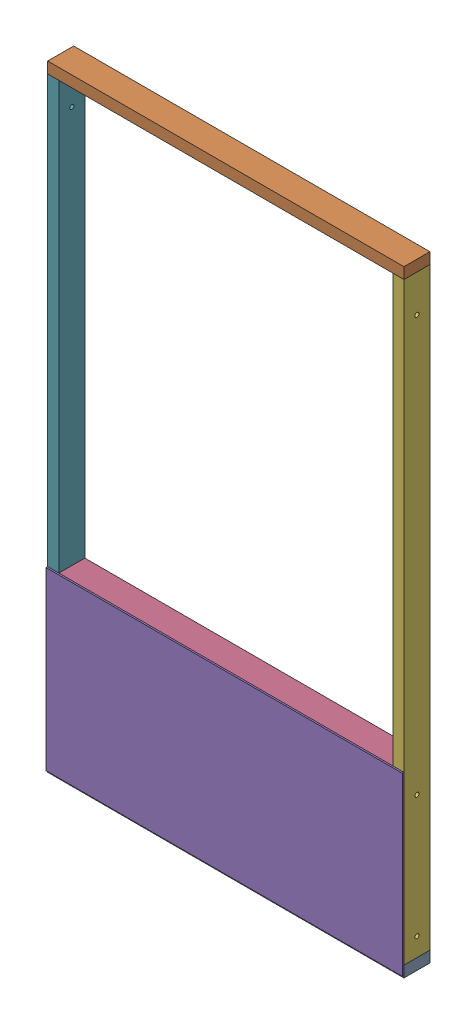
SolidWorks assembly basic panelC, configuration Default. Lengths in mm.
Overall size (1219.2 2108.2 94.46).
7 component instances, 6 part files, 34 mates.
Components (placement in the parent):
- 2x4x48-1: 2x4x48 [Default] x (0 0 -1) z (0 1 0) size (88.9 1219.2 38.1)
- 2x4x48-2: 2x4x48 [Default] at (0 2070.1 0) x (0 0 1) z (0 -1 0) size (88.9 1219.2 38.1)
- 2x4x21-1: 2x4x21 [Default] at (-609.6 552.45 0) x (0 0 -1) z (-1 0 0) size (88.9 533.4 38.1)
- 2x4x45-1: 2x4x45 [Default] at (-38.1 571.5 0) x (0 0 1) z (0 -1 0) size (88.9 1143 38.1)
- plywoodx48x23.7 plywood-1: plywoodx48x23.7 plywood [Default] at (-609.6 289.56 44.45) x (1 0 0) z (0 -1 0) size (1219.2 5.56 601.98)
- 2x4x80-HoleB-2: 2x4x80-HoleB [Default] at (-19.05 19.05 0) x (0 0 1) z (-1 0 0) size (88.9 2032 38.1)
- 2x4x80-Hole-2: 2x4x80-Hole [Default] at (-1200.15 19.05 0) x (0 0 -1) z (1 0 0) size (88.9 2032 38.1)
Mates (geometry in assembly coordinates):
- Coincident10: coincident anti-aligned: plane of 2x4x48-1 through (-1219.2 19.05 44.45) normal (0 1 0); plane of 2x4x21-1 through (-609.6 19.05 0) normal (0 -1 0)
- Coincident11: coincident aligned: plane of 2x4x48-1 through (-1219.2 19.05 44.45) normal (0 0 1); plane of 2x4x21-1 through (-628.65 19.05 44.45) normal (0 0 1)
- Coincident12: coincident anti-aligned: plane of 2x4x21-1 through (-609.6 552.45 0) normal (0 1 0); plane of 2x4x45-1 through (-1181.1 552.45 -44.45) normal (0 -1 0)
- Coincident13: coincident aligned: plane of 2x4x21-1 through (-628.65 19.05 44.45) normal (0 0 1); plane of 2x4x45-1 through (-1181.1 552.45 44.45) normal (0 0 1)
- Coincident18: coincident anti-aligned: plane of 2x4x48-1 through (-1219.2 19.05 44.45) normal (0 1 0); plane of 2x4x80-Hole-2 through (-1200.15 19.05 0) normal (0 -1 0)
- Coincident19: coincident aligned: plane of 2x4x48-1 through (-1219.2 0 0) normal (-1 0 0); plane of 2x4x80-Hole-2 through (-1219.2 2051.05 -44.45) normal (-1 0 0)
- Coincident20: coincident aligned: plane of 2x4x48-1 through (-1219.2 19.05 -44.45) normal (0 0 -1); plane of 2x4x80-Hole-2 through (-1219.2 2051.05 -44.45) normal (0 0 -1)
- Coincident21: coincident anti-aligned: plane of 2x4x48-1 through (-1219.2 19.05 44.45) normal (0 1 0); plane of 2x4x80-Hole-1 through (-19.05 19.05 0) normal (0 -1 0)
- Coincident22: coincident aligned: plane of 2x4x48-1 through (0 0 0) normal (1 0 0); plane of 2x4x80-Hole-1 through (0 2051.05 44.45) normal (1 0 0)
- Coincident24: coincident aligned: plane of 2x4x48-1 through (-1219.2 19.05 -44.45) normal (0 0 -1); plane of 2x4x80-Hole-1 through (0 2051.05 -44.45) normal (0 0 -1)
- Coincident26: coincident anti-aligned: plane of 2x4x45-1 through (-38.1 571.5 0) normal (1 0 0); plane of 2x4x80-Hole-1 through (-38.1 2051.05 44.45) normal (-1 0 0)
- Symmetric1: symmetric aligned: plane of 2x4x48-1 through (0 0 0) normal (1 0 0); plane of 2x4x21-1 through (-1219.2 0 0) normal (-1 0 0); plane of 2x4x48-1 through (-609.6 552.45 0) normal (-1 0 0)
- Coincident27: coincident anti-aligned: plane of 2x4x48-2 through (-1219.2 2051.05 -44.45) normal (0 -1 0); plane of 2x4x80-Hole-2 through (-1200.15 2051.05 0) normal (0 1 0)
- Coincident28: coincident aligned: plane of 2x4x48-2 through (-1219.2 2051.05 -44.45) normal (0 0 -1); plane of 2x4x80-Hole-2 through (-1219.2 2051.05 -44.45) normal (0 0 -1)
- Coincident29: coincident aligned: plane of 2x4x48-2 through (-1219.2 2070.1 0) normal (-1 0 0); plane of 2x4x80-Hole-2 through (-1219.2 2051.05 -44.45) normal (-1 0 0)
- Coincident30: coincident: plane of 2x4x48-2 through (-1219.2 2051.05 -44.45) normal (0 -1 0); plane of 2x4x80-HoleB-1 through (-1238.25 2051.05 0) normal (0 1 0)
- Coincident32: coincident: plane of 2x4x48-2 through (-1219.2 2051.05 -44.45) normal (0 0 -1); plane of 2x4x80-HoleB-1 through (-1257.3 2051.05 -44.45) normal (0 0 -1)
- Coincident33: coincident aligned: plane of 2x4x48-2 through (-1219.2 2051.05 -44.45) normal (0 0 -1); plane of 2x4x80-Hole-1 through (0 2051.05 -44.45) normal (0 0 -1)
- Coincident34: coincident: line of 2x4x48-2 through (-1219.2 2051.05 -44.45) axis (1 0 0); plane of 2x4x80-Hole-1 through (-19.05 2051.05 0) normal (0 1 0)
- Coincident35: coincident aligned: plane of 2x4x48-2 through (0 2070.1 0) normal (1 0 0); plane of 2x4x80-Hole-1 through (0 2051.05 44.45) normal (1 0 0)
- Coincident36: coincident aligned: plane of 2x4x48-2 through (-1219.2 2070.1 0) normal (-1 0 0); plane of 2x4x80-HoleB-1 through (-1219.2 2051.05 -44.45) normal (-1 0 0)
- Coincident37: coincident anti-aligned: plane of 2x4x48-1 through (-1219.2 19.05 44.45) normal (0 1 0); plane of 2x4x80-HoleB-2 through (-19.05 19.05 0) normal (0 -1 0)
- Coincident38: coincident aligned: plane of 2x4x48-1 through (-1219.2 19.05 -44.45) normal (0 0 -1); plane of 2x4x80-HoleB-2 through (-38.1 2051.05 -44.45) normal (0 0 -1)
- Coincident39: coincident aligned: plane of 2x4x48-1 through (0 0 0) normal (1 0 0); plane of 2x4x80-HoleB-2 through (0 2051.05 -44.45) normal (1 0 0)
- Coincident40: coincident aligned: plane of 2x4x80-HoleB-2 through (-38.1 2051.05 -44.45) normal (0 0 -1); plane of 2x4x80-Hole-2 through (-1181.1 2051.05 -44.45) normal (0 0 -1)
- Coincident41: coincident anti-aligned: plane of 2x4x45-1 through (-1181.1 571.5 0) normal (-1 0 0); plane of 2x4x80-Hole-2 through (-1181.1 2051.05 44.45) normal (1 0 0)
- Coincident42: coincident anti-aligned: plane of 2x4x48-1 through (-1219.2 19.05 44.45) normal (0 1 0); plane of 2x4x80-Hole-2 through (-1200.15 19.05 0) normal (0 -1 0)
- Coincident43: coincident aligned: plane of 2x4x48-2 through (-1219.2 2051.05 -44.45) normal (0 0 -1); plane of 2x4x80-Hole-2 through (-1181.1 2051.05 -44.45) normal (0 0 -1)
- Coincident44: coincident aligned: plane of 2x4x48-2 through (-1219.2 2070.1 0) normal (-1 0 0); plane of 2x4x80-Hole-2 through (-1219.2 2051.05 44.45) normal (-1 0 0)
- Coincident45: coincident anti-aligned: plane of 2x4x48-2 through (-1219.2 2051.05 -44.45) normal (0 -1 0); plane of 2x4x80-Hole-2 through (-1200.15 2051.05 0) normal (0 1 0)
- Coincident46: coincident aligned: plane of 2x4x48-2 through (0 2070.1 0) normal (1 0 0); plane of 2x4x80-HoleB-2 through (0 2051.05 -44.45) normal (1 0 0)
- Distance1: distance = 7.62 mm aligned: plane of plywoodx48x23.7 plywood-1 through (-1219.2 -11.43 50.0063) normal (0 -1 0); plane of 2x4x48-1 through (-1219.2 -19.05 44.45) normal (0 -1 0)
- Coincident47: coincident aligned: plane of plywoodx48x23.7 plywood-1 through (0 -11.43 50.0063) normal (1 0 0); plane of 2x4x80-HoleB-2 through (0 2051.05 -44.45) normal (1 0 0)
- Coincident48: coincident anti-aligned: plane of plywoodx48x23.7 plywood-1 through (-609.6 289.56 44.45) normal (0 0 -1); plane of 2x4x80-HoleB-2 through (-38.1 2051.05 44.45) normal (0 0 1)
